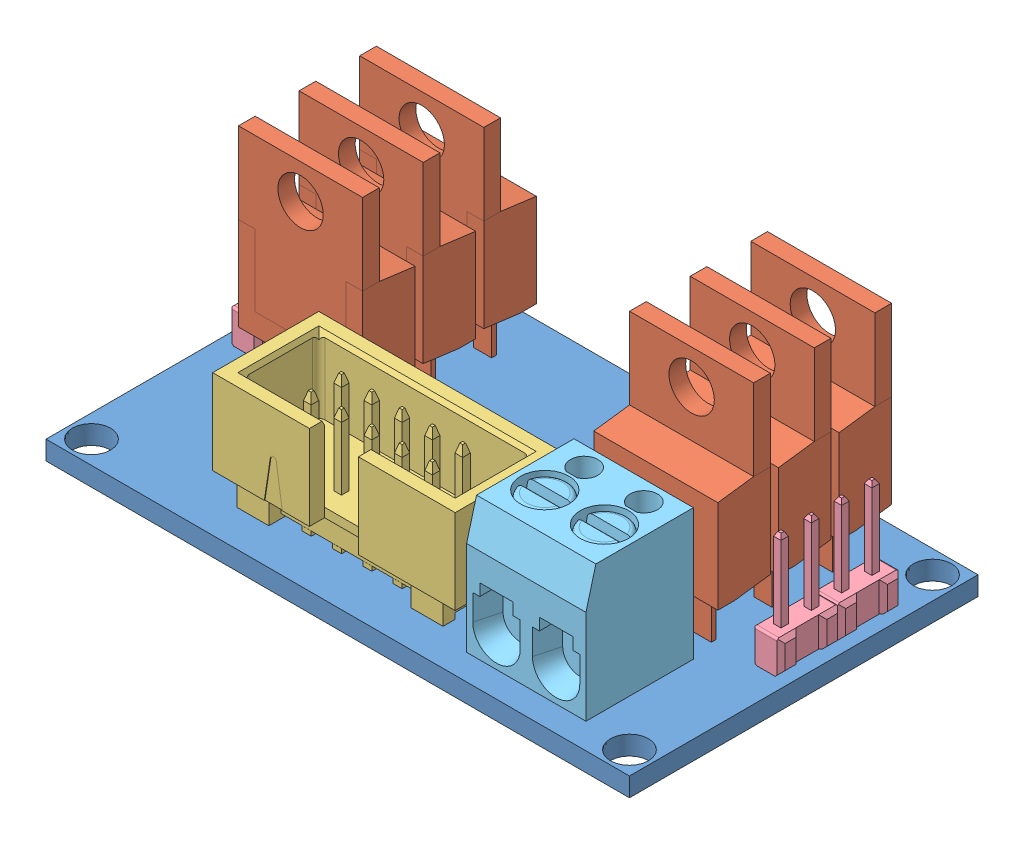
SolidWorks assembly Nonaddressable Controller, configuration Default. Lengths in mm.
Overall size (48.89 23.5 29.21).
13 component instances, 5 part files, 41 mates.
Components (placement in the parent):
- Nonaddressable Controller PCB-1: Nonaddressable Controller PCB [Default] at (4.9576 24.2591 44.8607) size (48.9 1.59 29.21)
- TO-220-1: TO-220 [Default] at (-9.9649 25.8466 42.5807) x (-1 0 0) z (0 0 -1) size (10.4 22 4.4)
- TO-220-2: TO-220 [Default] at (-9.9649 25.8466 37.5007) x (-1 0 0) z (0 0 -1) size (10.4 22 4.4)
- TO-220-3: TO-220 [Default] at (-9.9649 25.8466 47.6607) x (-1 0 0) z (0 0 -1) size (10.4 22 4.4)
- TO-220-4: TO-220 [Default] at (19.8801 25.8466 38.2507) size (10.4 22 4.4)
- TO-220-5: TO-220 [Default] at (19.8801 25.8466 33.1707) size (10.4 22 4.4)
- TO-220-6: TO-220 [Default] at (19.8801 25.8466 43.3307) size (10.4 22 4.4)
- 702461001-1: 702461001 [Default] at (2.1001 31.5606 52.4807) size (20.32 12.7 8.89)
- Pin Header 2x1 TH Pitch 2.54mm-1: Pin Header 2x1 TH Pitch 2.54mm [Default] at (-17.5849 25.8452 42.3207) x (1 0 0) z (0 1 0) size (2.54 5.08 12.7)
- Pin Header 2x1 TH Pitch 2.54mm-2: Pin Header 2x1 TH Pitch 2.54mm [Default] at (-17.5849 25.8452 37.2407) x (1 0 0) z (0 1 0) size (2.54 5.08 12.7)
- Pin Header 2x1 TH Pitch 2.54mm-3: Pin Header 2x1 TH Pitch 2.54mm [Default] at (27.5001 25.8452 43.5907) x (-1 0 0) z (0 1 0) size (2.54 5.08 12.7)
- Pin Header 2x1 TH Pitch 2.54mm-4: Pin Header 2x1 TH Pitch 2.54mm [Default] at (27.5001 25.8452 38.5107) x (-1 0 0) z (0 1 0) size (2.54 5.08 12.7)
- 237-102-1: 237-102 [Default] at (23.6101 25.8466 53.1157) x (0 0 1) z (-1 0 0) size (9 15.5 10)
Mates (geometry in assembly coordinates):
- Coincident1: coincident anti-aligned: plane of Nonaddressable Controller PCB-1 through (4.9576 25.8466 44.8607) normal (0 1 0); plane of TO-220-3 through (-6.7149 25.8466 44.6607) normal (0 -1 0)
- Coincident2: coincident anti-aligned: plane of Nonaddressable Controller PCB-1 through (4.9576 25.8466 44.8607) normal (0 1 0); plane of TO-220-1 through (-6.7149 25.8466 39.5807) normal (0 -1 0)
- Coincident3: coincident anti-aligned: plane of Nonaddressable Controller PCB-1 through (4.9576 25.8466 44.8607) normal (0 1 0); plane of TO-220-2 through (-6.7149 25.8466 34.5007) normal (0 -1 0)
- Coincident4: coincident anti-aligned: plane of Nonaddressable Controller PCB-1 through (4.9576 25.8466 44.8607) normal (0 1 0); plane of TO-220-5 through (23.1301 25.8466 36.1707) normal (0 -1 0)
- Coincident5: coincident anti-aligned: plane of Nonaddressable Controller PCB-1 through (4.9576 25.8466 44.8607) normal (0 1 0); plane of TO-220-6 through (23.1301 25.8466 46.3307) normal (0 -1 0)
- Coincident6: coincident anti-aligned: plane of Nonaddressable Controller PCB-1 through (4.9576 25.8466 44.8607) normal (0 1 0); plane of TO-220-4 through (18.1301 25.8466 41.2507) normal (0 -1 0)
- Coincident7: coincident aligned: plane of TO-220-1 through (-15.1649 29.8466 38.1807) normal (-1 0 0); plane of TO-220-3 through (-15.1649 29.8466 43.2607) normal (-1 0 0)
- Coincident8: coincident aligned: plane of TO-220-1 through (-15.1649 29.8466 38.1807) normal (-1 0 0); plane of TO-220-2 through (-15.1649 29.8466 33.1007) normal (-1 0 0)
- Coincident9: coincident aligned: plane of TO-220-4 through (25.0801 29.8466 42.6507) normal (1 0 0); plane of TO-220-5 through (25.0801 29.8466 37.5707) normal (1 0 0)
- Coincident10: coincident aligned: plane of TO-220-5 through (25.0801 29.8466 37.5707) normal (1 0 0); plane of TO-220-6 through (25.0801 29.8466 47.7307) normal (1 0 0)
- Distance1: distance = 9.525 mm: line of TO-220-3 through (-9.9649 22.8466 44.8607) axis (0 -1 0); plane of Nonaddressable Controller PCB-1 through (-19.4899 25.8466 30.2557) normal (-1 0 0)
- Distance2: distance = 14.605 mm: line of TO-220-3 through (-9.9649 22.8466 44.8607) axis (0 -1 0); plane of Nonaddressable Controller PCB-1 through (-19.4899 25.8466 59.4657) normal (0 0 1)
- Parallel1: parallel aligned: plane of Nonaddressable Controller PCB-1 through (-19.4899 25.8466 59.4657) normal (0 0 1); plane of TO-220-3 through (-4.7649 38.0466 47.6607) normal (0 0 1)
- Distance3: distance = 19.685 mm: line of TO-220-1 through (-9.9649 22.8466 39.7807) axis (0 -1 0); plane of Nonaddressable Controller PCB-1 through (-19.4899 25.8466 59.4657) normal (0 0 1)
- Distance4: distance = 24.765 mm: line of TO-220-2 through (-9.9649 22.8466 34.7007) axis (0 -1 0); plane of Nonaddressable Controller PCB-1 through (-19.4899 25.8466 59.4657) normal (0 0 1)
- Distance5: distance = 39.37 mm: line of TO-220-6 through (19.8801 22.8466 46.1307) axis (0 -1 0); plane of Nonaddressable Controller PCB-1 through (-19.4899 25.8466 30.2557) normal (-1 0 0)
- Distance6: distance = 13.335 mm: line of TO-220-6 through (19.8801 22.8466 46.1307) axis (0 -1 0); plane of Nonaddressable Controller PCB-1 through (-19.4899 25.8466 59.4657) normal (0 0 1)
- Parallel2: parallel aligned: plane of Nonaddressable Controller PCB-1 through (-19.4899 25.8466 59.4657) normal (0 0 1); plane of TO-220-6 through (14.6801 38.0466 47.7307) normal (0 0 1)
- Distance7: distance = 18.415 mm: line of TO-220-4 through (19.8801 22.8466 41.0507) axis (0 -1 0); plane of Nonaddressable Controller PCB-1 through (-19.4899 25.8466 59.4657) normal (0 0 1)
- Distance8: distance = 23.495 mm: line of TO-220-5 through (19.8801 22.8466 35.9707) axis (0 -1 0); plane of Nonaddressable Controller PCB-1 through (-19.4899 25.8466 59.4657) normal (0 0 1)
- Coincident21: coincident anti-aligned: plane of Nonaddressable Controller PCB-1 through (4.9576 25.8466 44.8607) normal (0 1 0); plane of 702461001-1 through (-8.0599 25.8466 48.0357) normal (0 -1 0)
- Distance9: distance = 21.59 mm: point of 702461001-1; plane of Nonaddressable Controller PCB-1 through (-19.4899 25.8466 30.2557) normal (-1 0 0)
- Distance10: distance = 6.985 mm: point of 702461001-1; plane of Nonaddressable Controller PCB-1 through (-19.4899 25.8466 59.4657) normal (0 0 1)
- Coincident24: coincident anti-aligned: plane of Nonaddressable Controller PCB-1 through (4.9576 25.8466 44.8607) normal (0 1 0); plane of Pin Header 2x1 TH Pitch 2.54mm-2 through (-18.382 25.8466 39.7907) normal (0 -1 0)
- Coincident25: coincident anti-aligned: plane of Nonaddressable Controller PCB-1 through (4.9576 25.8466 44.8607) normal (0 1 0); plane of Pin Header 2x1 TH Pitch 2.54mm-1 through (-18.382 25.8466 39.7707) normal (0 -1 0)
- Coincident26: coincident anti-aligned: plane of Pin Header 2x1 TH Pitch 2.54mm-1 through (-18.5279 25.8186 39.7807) normal (0 0 -1); plane of Pin Header 2x1 TH Pitch 2.54mm-2 through (-18.5279 25.8186 39.7807) normal (0 0 1)
- Coincident27: coincident aligned: plane of Pin Header 2x1 TH Pitch 2.54mm-1 through (-18.8549 28.3194 41.9937) normal (-1 0 0); plane of Pin Header 2x1 TH Pitch 2.54mm-2 through (-18.8549 28.3194 39.4537) normal (-1 0 0)
- Distance11: distance = 1.905 mm: line of Pin Header 2x1 TH Pitch 2.54mm-1 through (-17.5849 22.6452 43.5907) axis (0 -1 0); plane of Nonaddressable Controller PCB-1 through (-19.4899 25.8466 30.2557) normal (-1 0 0)
- Distance12: distance = 15.875 mm: line of Pin Header 2x1 TH Pitch 2.54mm-1 through (-17.5849 22.6452 43.5907) axis (0 -1 0); plane of Nonaddressable Controller PCB-1 through (-19.4899 25.8466 59.4657) normal (0 0 1)
- Coincident30: coincident anti-aligned: plane of Nonaddressable Controller PCB-1 through (4.9576 25.8466 44.8607) normal (0 1 0); plane of Pin Header 2x1 TH Pitch 2.54mm-4 through (28.2971 25.8466 41.0607) normal (0 -1 0)
- Coincident31: coincident anti-aligned: plane of Nonaddressable Controller PCB-1 through (4.9576 25.8466 44.8607) normal (0 1 0); plane of Pin Header 2x1 TH Pitch 2.54mm-3 through (28.2971 25.8466 41.0407) normal (0 -1 0)
- Coincident32: coincident anti-aligned: plane of Pin Header 2x1 TH Pitch 2.54mm-3 through (28.4431 25.8186 41.0507) normal (0 0 -1); plane of Pin Header 2x1 TH Pitch 2.54mm-4 through (28.4431 25.8186 41.0507) normal (0 0 1)
- Coincident33: coincident aligned: plane of Pin Header 2x1 TH Pitch 2.54mm-3 through (26.2301 28.3194 41.3776) normal (-1 0 0); plane of Pin Header 2x1 TH Pitch 2.54mm-4 through (26.2301 28.3194 38.8376) normal (-1 0 0)
- Distance13: distance = 22.225 mm: line of Pin Header 2x1 TH Pitch 2.54mm-4 through (27.5001 22.6452 37.2407) axis (0 -1 0); plane of Nonaddressable Controller PCB-1 through (-19.4899 25.8466 59.4657) normal (0 0 1)
- Distance14: distance = 46.99 mm: line of Pin Header 2x1 TH Pitch 2.54mm-4 through (27.5001 22.6452 37.2407) axis (0 -1 0); plane of Nonaddressable Controller PCB-1 through (-19.4899 25.8466 30.2557) normal (-1 0 0)
- Parallel3: parallel aligned: plane of Nonaddressable Controller PCB-1 through (29.4051 25.8466 30.2557) normal (1 0 0); plane of Pin Header 2x1 TH Pitch 2.54mm-3 through (28.7701 28.3194 43.9176) normal (1 0 0)
- Parallel4: parallel aligned: plane of Nonaddressable Controller PCB-1 through (-19.4899 25.8466 30.2557) normal (-1 0 0); plane of Pin Header 2x1 TH Pitch 2.54mm-1 through (-18.8549 28.3194 44.5337) normal (-1 0 0)
- Coincident34: coincident anti-aligned: plane of Nonaddressable Controller PCB-1 through (4.9576 25.8466 44.8607) normal (0 1 0); plane of 237-102-1 through (13.6101 25.8466 48.3157) normal (0 -1 0)
- Parallel5: parallel aligned: plane of Nonaddressable Controller PCB-1 through (-19.4899 25.8466 59.4657) normal (0 0 1); plane of 237-102-1 through (13.6101 25.8466 57.3157) normal (0 0 1)
- Distance15: distance = 7.62 mm: line of 237-102-1 through (18.6101 25.8466 51.8457) axis (0 -1 0); plane of Nonaddressable Controller PCB-1 through (-19.4899 25.8466 59.4657) normal (0 0 1)
- Distance16: distance = 38.1 mm: line of 237-102-1 through (18.6101 25.8466 51.8457) axis (0 -1 0); plane of Nonaddressable Controller PCB-1 through (-19.4899 25.8466 30.2557) normal (-1 0 0)
